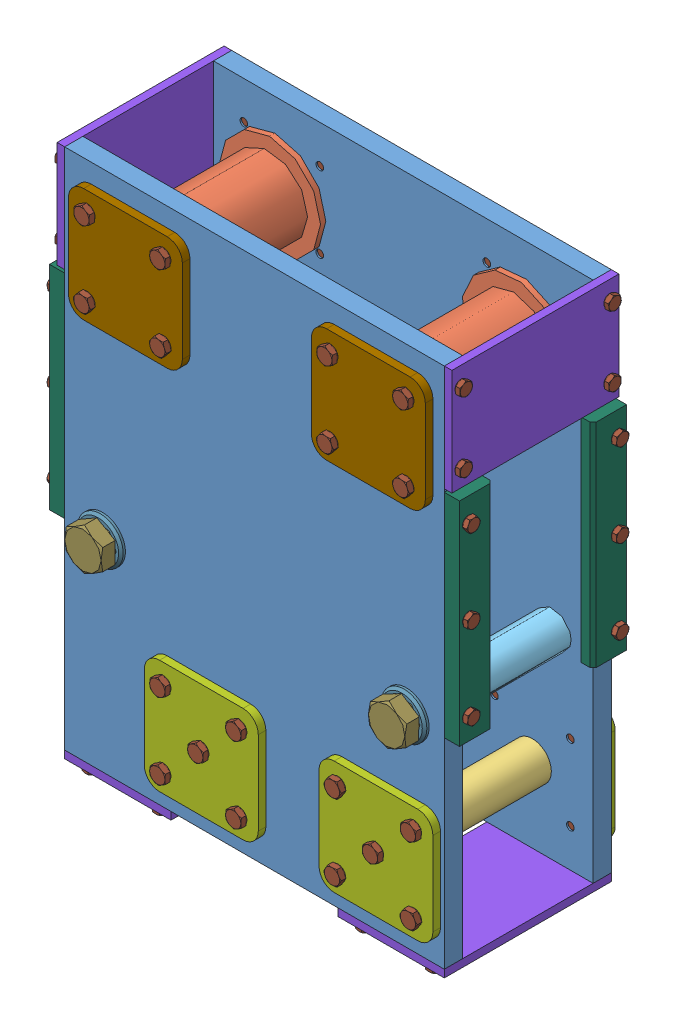
SolidWorks assembly 010200_trolley, configuration Default. Lengths in mm.
Overall size (277 352.5 150).
103 component instances, 15 part files, 227 mates.
Components (placement in the parent):
- 010201_trolley_main_plate-3: 010201_trolley_main_plate [Default] at (-125 -294 43) size (250 344 12)
- 010201_trolley_main_plate-1: 010201_trolley_main_plate [Default] at (-125 -294 -55) size (250 344 12)
- 010202_trolley_roller-1: 010202_trolley_roller [Default] at (-205 -50 0) size (67 67 105)
- 010202_trolley_roller-2: 010202_trolley_roller [Default] at (-45 -50 0) x (0.985719 -0.1684 0) z (0 0 1) size (67 67 105)
- 010203_trolley_cylinder_pin-1: 010203_trolley_cylinder_pin [Default] at (-40 -294 0) size (25 25 110)
- 010203_trolley_cylinder_pin-3: 010203_trolley_cylinder_pin [Default] at (-155 -294 0) size (25 25 110)
- 010204_trolley_winch-1: 010204_trolley_winch [Default] at (-155 -294 0) x (0 0 1) z (0 1 0) size (30 100 100)
- 010205_trolley_small_roll-2: 010205_trolley_small_roll [Default] at (-25 -211 0) size (24 24 83)
- 010205_trolley_small_roll-3: 010205_trolley_small_roll [Default] at (-225 -211 0) size (24 24 83)
- 010207_trolley_distance_sleeve-2: 010207_trolley_distance_sleeve [Default] at (-155 -294 29.5) size (32 32 27)
- 010207_trolley_distance_sleeve-1: 010207_trolley_distance_sleeve [Default] at (-155 -294 -29.5) size (32 32 27)
- 010209_trolley_pincover-6: 010209_trolley_pincover [Default] at (-40 -294 -55) x (0 1 0) z (0 0 -1) size (75 75 5)
- 010209_trolley_pincover-7: 010209_trolley_pincover [Default] at (-155 -294 55) x (-1 0 0) z (0 0 1) size (75 75 5)
- 010209_trolley_pincover-8: 010209_trolley_pincover [Default] at (-155 -294 -55) x (1 0 0) z (0 0 -1) size (75 75 5)
- 010210_trolley_front_plate-4: 010210_trolley_front_plate [Default] at (-252.5 -35 0) x (0 0 1) z (-1 0 0) size (110 70 5)
- 010210_trolley_front_plate-8: 010210_trolley_front_plate [Default] at (2.5 -35 0) x (0 0 -1) z (1 0 0) size (110 70 5)
- 010210_trolley_front_plate-9: 010210_trolley_front_plate [Default] at (-35 -346.5 0) x (0 0 1) z (0 -1 0) size (110 70 5)
- 010210_trolley_front_plate-10: 010210_trolley_front_plate [Default] at (-215 -346.5 0) x (0 0 1) z (0 -1 0) size (110 70 5)
- 010208_trolley_bearing_cover-1: 010208_trolley_bearing_cover [Default] at (-205 -50 55) size (75 75 5)
- 010208_trolley_bearing_cover-7: 010208_trolley_bearing_cover [Default] at (-45 -50 55) size (75 75 5)
- 010208_trolley_bearing_cover-8: 010208_trolley_bearing_cover [Default] at (-45 -50 -55) x (-1 0 0) z (0 0 -1) size (75 75 5)
- 010208_trolley_bearing_cover-9: 010208_trolley_bearing_cover [Default] at (-205 -50 -55) x (-1 0 0) z (0 0 -1) size (75 75 5)
- SKF_6005_2z-1: SKF_6005_2z [Default] at (-45 -50 -52.5) size (47 47 12)
- SKF_6005_2z-2: SKF_6005_2z [Default] at (-205 -50 -52.5) size (47 47 12)
- SKF_6005_2z-3: SKF_6005_2z [Default] at (-205 -50 40.5) size (47 47 12)
- SKF_6005_2z-4: SKF_6005_2z [Default] at (-45 -50 40.5) size (47 47 12)
- 010209_trolley_pincover-9: 010209_trolley_pincover [Default] at (-40 -294 55) x (0 -1 0) z (0 0 1) size (75 75 5)
- hex screw gradeab_iso-78: hex screw gradeab_iso [ISO 4017 - M6 x 16-N] at (-40 -294 64) x (0 0 -1) z (1 0 0) size (20 11.55 10)
- hex screw gradeab_iso-79: hex screw gradeab_iso [ISO 4017 - M6 x 16-N] at (-155 -294 -64) x (0 0 1) z (-0.804894 -0.593418 0) size (20 11.55 10)
- hex screw gradeab_iso-80: hex screw gradeab_iso [ISO 4017 - M6 x 16-N] at (-40 -294 -64) x (0 0 1) z (-0.923728 -0.383049 0) size (20 11.55 10)
- hex screw gradeab_iso-81: hex screw gradeab_iso [ISO 4017 - M6 x 16-N] at (-155 -294 64) x (0 0 -1) z (1 0 0) size (20 11.55 10)
- hex bolt gradeab_iso-3: hex bolt gradeab_iso [ISO 4014 - M16 x 140 x 44-N] at (-225 -211 68) x (0 0 -1) z (1 0 0) size (150 27.71 24)
- hex nut style 1 gradeab_iso-1: hex nut style 1 gradeab_iso [ISO - 4032 - M16 - W - N] at (-225 -211 -72.8) x (-1 0 0) z (0 0 -1) size (24 27.71 14.8)
- hex nut style 1 gradeab_iso-4: hex nut style 1 gradeab_iso [ISO - 4032 - M16 - W - N] at (-25 -211 -72.8) x (-0.534174 -0.845375 0) z (0 0 -1) size (24 27.71 14.8)
- plain washer chamfered grade a_iso-7: plain washer chamfered grade a_iso [Washer ISO 7090 - 16] at (-25 -211 55) x (0 0 -1) z (0.534174 0.845375 0) size (3 30 30)
- plain washer chamfered grade a_iso-8: plain washer chamfered grade a_iso [Washer ISO 7090 - 16] at (-25 -211 -55) x (0 0 1) z (-1 0 0) size (3 30 30)
- hex bolt gradeab_iso-4: hex bolt gradeab_iso [ISO 4014 - M16 x 140 x 44-N] at (-25 -211 68) x (0 0 -1) z (0.534174 0.845375 0) size (150 27.71 24)
- plain washer chamfered grade a_iso-4: plain washer chamfered grade a_iso [Washer ISO 7090 - 16] at (-225 -211 55) x (0 0 -1) z (1 0 0) size (3 30 30)
- plain washer chamfered grade a_iso-6: plain washer chamfered grade a_iso [Washer ISO 7090 - 16] at (-225 -211 -55) x (0 0 1) z (-1 0 0) size (3 30 30)
- hex screw gradeab_iso-98: hex screw gradeab_iso [ISO 4017 - M5 x 16-N] at (13.5 -142 49) x (-1 0 0) z (0 0 -1) size (19.5 9.24 8)
- hex screw gradeab_iso-99: hex screw gradeab_iso [ISO 4017 - M5 x 16-N] at (13.5 -87 49) x (-1 0 0) z (0 0.461604 0.887086) size (19.5 9.24 8)
- hex screw gradeab_iso-100: hex screw gradeab_iso [ISO 4017 - M5 x 16-N] at (13.5 -197 49) x (-1 0 0) z (0 -0.924225 -0.381849) size (19.5 9.24 8)
- hex screw gradeab_iso-101: hex screw gradeab_iso [ISO 4017 - M5 x 16-N] at (-263.5 -87 -49) x (1 0 0) z (0 0.461604 -0.887086) size (19.5 9.24 8)
- hex screw gradeab_iso-102: hex screw gradeab_iso [ISO 4017 - M5 x 16-N] at (-263.5 -197 -49) x (1 0 0) z (0 -0.924225 0.381849) size (19.5 9.24 8)
- hex screw gradeab_iso-103: hex screw gradeab_iso [ISO 4017 - M5 x 16-N] at (-263.5 -142 -49) size (19.5 9.24 8)
- hex screw gradeab_iso-104: hex screw gradeab_iso [ISO 4017 - M5 x 16-N] at (-263.5 -197 49) x (1 0 0) z (0 -0.461604 0.887086) size (19.5 9.24 8)
- hex screw gradeab_iso-105: hex screw gradeab_iso [ISO 4017 - M5 x 16-N] at (-263.5 -87 49) x (1 0 0) z (0 0.924225 -0.381849) size (19.5 9.24 8)
- hex screw gradeab_iso-106: hex screw gradeab_iso [ISO 4017 - M5 x 16-N] at (-263.5 -142 49) x (1 0 0) z (0 0 -1) size (19.5 9.24 8)
- hex screw gradeab_iso-107: hex screw gradeab_iso [ISO 4017 - M5 x 16-N] at (13.5 -197 -49) x (-1 0 0) z (0 -0.461604 -0.887086) size (19.5 9.24 8)
- hex screw gradeab_iso-108: hex screw gradeab_iso [ISO 4017 - M5 x 16-N] at (13.5 -87 -49) x (-1 0 0) z (0 0.924225 0.381849) size (19.5 9.24 8)
- hex screw gradeab_iso-109: hex screw gradeab_iso [ISO 4017 - M5 x 16-N] at (13.5 -142 -49) x (-1 0 0) z (0 0 1) size (19.5 9.24 8)
- hex screw gradeab_iso-65: hex screw gradeab_iso [ISO 4017 - M6 x 16-N] at (-15 -319 -64) x (0 0 1) z (0 1 0) size (20 11.55 10)
- hex screw gradeab_iso-66: hex screw gradeab_iso [ISO 4017 - M6 x 16-N] at (-15 -269 -64) x (0 0 1) z (-0.923728 -0.383049 0) size (20 11.55 10)
- hex screw gradeab_iso-67: hex screw gradeab_iso [ISO 4017 - M6 x 16-N] at (-65 -269 -64) x (0 0 1) z (0 1 0) size (20 11.55 10)
- hex screw gradeab_iso-68: hex screw gradeab_iso [ISO 4017 - M6 x 16-N] at (-65 -319 -64) x (0 0 1) z (0 1 0) size (20 11.55 10)
- hex screw gradeab_iso-82: hex screw gradeab_iso [ISO 4017 - M5 x 16-N] at (-258.5 -12 49) x (1 0 0) z (0 0.924225 0.381849) size (19.5 9.24 8)
- hex screw gradeab_iso-83: hex screw gradeab_iso [ISO 4017 - M5 x 16-N] at (-258.5 -12 -49) size (19.5 9.24 8)
- hex screw gradeab_iso-84: hex screw gradeab_iso [ISO 4017 - M5 x 16-N] at (-258.5 -58 49) size (19.5 9.24 8)
- hex screw gradeab_iso-85: hex screw gradeab_iso [ISO 4017 - M5 x 16-N] at (-258.5 -58 -49) size (19.5 9.24 8)
- hex screw gradeab_iso-90: hex screw gradeab_iso [ISO 4017 - M5 x 16-N] at (8.5 -12 -49) x (-1 0 0) z (0 0.93115 -0.364637) size (19.5 9.24 8)
- hex screw gradeab_iso-91: hex screw gradeab_iso [ISO 4017 - M5 x 16-N] at (8.5 -12 49) x (-1 0 0) z (0 0 -1) size (19.5 9.24 8)
- hex screw gradeab_iso-92: hex screw gradeab_iso [ISO 4017 - M5 x 16-N] at (8.5 -58 -49) x (-1 0 0) z (0 0 -1) size (19.5 9.24 8)
- hex screw gradeab_iso-93: hex screw gradeab_iso [ISO 4017 - M5 x 16-N] at (8.5 -58 49) x (-1 0 0) z (0 0 -1) size (19.5 9.24 8)
- hex screw gradeab_iso-86: hex screw gradeab_iso [ISO 4017 - M5 x 16-N] at (-58 -352.5 49) x (0 1 0) z (-0.924225 0 0.381849) size (19.5 9.24 8)
- hex screw gradeab_iso-87: hex screw gradeab_iso [ISO 4017 - M5 x 16-N] at (-58 -352.5 -49) x (0 1 0) z (0 0 1) size (19.5 9.24 8)
- hex screw gradeab_iso-88: hex screw gradeab_iso [ISO 4017 - M5 x 16-N] at (-12 -352.5 49) x (0 1 0) z (0 0 1) size (19.5 9.24 8)
- hex screw gradeab_iso-89: hex screw gradeab_iso [ISO 4017 - M5 x 16-N] at (-12 -352.5 -49) x (0 1 0) z (0 0 1) size (19.5 9.24 8)
- hex screw gradeab_iso-94: hex screw gradeab_iso [ISO 4017 - M5 x 16-N] at (-238 -352.5 49) x (0 1 0) z (-0.924225 0 0.381849) size (19.5 9.24 8)
- hex screw gradeab_iso-95: hex screw gradeab_iso [ISO 4017 - M5 x 16-N] at (-238 -352.5 -49) x (0 1 0) z (0 0 1) size (19.5 9.24 8)
- hex screw gradeab_iso-96: hex screw gradeab_iso [ISO 4017 - M5 x 16-N] at (-192 -352.5 49) x (0 1 0) z (0 0 1) size (19.5 9.24 8)
- hex screw gradeab_iso-97: hex screw gradeab_iso [ISO 4017 - M5 x 16-N] at (-192 -352.5 -49) x (0 1 0) z (0 0 1) size (19.5 9.24 8)
- hex screw gradeab_iso-25: hex screw gradeab_iso [ISO 4017 - M6 x 16-N] at (-180 -25 64) x (0 0 -1) z (1 0 0) size (20 11.55 10)
- hex screw gradeab_iso-26: hex screw gradeab_iso [ISO 4017 - M6 x 16-N] at (-230 -25 64) x (0 0 -1) z (1 0 0) size (20 11.55 10)
- hex screw gradeab_iso-27: hex screw gradeab_iso [ISO 4017 - M6 x 16-N] at (-230 -75 64) x (0 0 -1) z (0.923728 0.383049 0) size (20 11.55 10)
- hex screw gradeab_iso-28: hex screw gradeab_iso [ISO 4017 - M6 x 16-N] at (-180 -75 64) x (0 0 -1) z (0.923728 0.383049 0) size (20 11.55 10)
- hex screw gradeab_iso-29: hex screw gradeab_iso [ISO 4017 - M6 x 16-N] at (-20 -25 64) x (0 0 -1) z (1 0 0) size (20 11.55 10)
- hex screw gradeab_iso-30: hex screw gradeab_iso [ISO 4017 - M6 x 16-N] at (-70 -25 64) x (0 0 -1) z (1 0 0) size (20 11.55 10)
- hex screw gradeab_iso-31: hex screw gradeab_iso [ISO 4017 - M6 x 16-N] at (-70 -75 64) x (0 0 -1) z (0.923728 0.383049 0) size (20 11.55 10)
- hex screw gradeab_iso-32: hex screw gradeab_iso [ISO 4017 - M6 x 16-N] at (-20 -75 64) x (0 0 -1) z (0.923728 0.383049 0) size (20 11.55 10)
- hex screw gradeab_iso-33: hex screw gradeab_iso [ISO 4017 - M6 x 16-N] at (-70 -25 -64) x (0 0 1) z (-1 0 0) size (20 11.55 10)
- hex screw gradeab_iso-34: hex screw gradeab_iso [ISO 4017 - M6 x 16-N] at (-20 -25 -64) x (0 0 1) z (0.544188 0.838963 0) size (20 11.55 10)
- hex screw gradeab_iso-35: hex screw gradeab_iso [ISO 4017 - M6 x 16-N] at (-20 -75 -64) x (0 0 1) z (-0.923728 0.383049 0) size (20 11.55 10)
- hex screw gradeab_iso-36: hex screw gradeab_iso [ISO 4017 - M6 x 16-N] at (-70 -75 -64) x (0 0 1) z (-0.923728 0.383049 0) size (20 11.55 10)
- hex screw gradeab_iso-37: hex screw gradeab_iso [ISO 4017 - M6 x 16-N] at (-230 -25 -64) x (0 0 1) z (-1 0 0) size (20 11.55 10)
- hex screw gradeab_iso-38: hex screw gradeab_iso [ISO 4017 - M6 x 16-N] at (-180 -25 -64) x (0 0 1) z (-0.088811 0.996049 0) size (20 11.55 10)
- hex screw gradeab_iso-39: hex screw gradeab_iso [ISO 4017 - M6 x 16-N] at (-180 -75 -64) x (0 0 1) z (-0.923728 0.383049 0) size (20 11.55 10)
- hex screw gradeab_iso-40: hex screw gradeab_iso [ISO 4017 - M6 x 16-N] at (-230 -75 -64) x (0 0 1) z (-0.923728 0.383049 0) size (20 11.55 10)
- hex screw gradeab_iso-62: hex screw gradeab_iso [ISO 4017 - M6 x 16-N] at (-15 -269 64) x (0 0 -1) z (1 0 0) size (20 11.55 10)
- hex screw gradeab_iso-61: hex screw gradeab_iso [ISO 4017 - M6 x 16-N] at (-15 -319 64) x (0 0 -1) z (0 -1 0) size (20 11.55 10)
- hex screw gradeab_iso-63: hex screw gradeab_iso [ISO 4017 - M6 x 16-N] at (-65 -319 64) x (0 0 -1) z (0 -1 0) size (20 11.55 10)
- hex screw gradeab_iso-64: hex screw gradeab_iso [ISO 4017 - M6 x 16-N] at (-65 -269 64) x (0 0 -1) z (0 -1 0) size (20 11.55 10)
- hex screw gradeab_iso-69: hex screw gradeab_iso [ISO 4017 - M6 x 16-N] at (-130 -319 64) x (0 0 -1) z (-1 0 0) size (20 11.55 10)
- hex screw gradeab_iso-70: hex screw gradeab_iso [ISO 4017 - M6 x 16-N] at (-180 -319 64) x (0 0 -1) z (-1 0 0) size (20 11.55 10)
- hex screw gradeab_iso-71: hex screw gradeab_iso [ISO 4017 - M6 x 16-N] at (-180 -269 64) x (0 0 -1) z (-1 0 0) size (20 11.55 10)
- hex screw gradeab_iso-72: hex screw gradeab_iso [ISO 4017 - M6 x 16-N] at (-130 -269 64) x (0 0 -1) z (-1 0 0) size (20 11.55 10)
- hex screw gradeab_iso-73: hex screw gradeab_iso [ISO 4017 - M6 x 16-N] at (-180 -319 -64) x (0 0 1) z (1 0 0) size (20 11.55 10)
- hex screw gradeab_iso-74: hex screw gradeab_iso [ISO 4017 - M6 x 16-N] at (-130 -319 -64) x (0 0 1) z (1 0 0) size (20 11.55 10)
- hex screw gradeab_iso-75: hex screw gradeab_iso [ISO 4017 - M6 x 16-N] at (-130 -269 -64) x (0 0 1) z (1 0 0) size (20 11.55 10)
- hex screw gradeab_iso-76: hex screw gradeab_iso [ISO 4017 - M6 x 16-N] at (-180 -269 -64) x (0 0 1) z (-0.677902 -0.735152 0) size (20 11.55 10)
- 010206_trolley_guide-1: 010206_trolley_guide [Default] at (0 -142 44) x (0 0 -1) z (1 0 0) size (22 140 10)
- 010206_trolley_guide-5: 010206_trolley_guide [Default] at (-250 -142 -44) x (0 0 1) z (-1 0 0) size (22 140 10)
- 010206_trolley_guide-6: 010206_trolley_guide [Default] at (-250 -142 44) x (0 0 -1) z (-1 0 0) size (22 140 10)
- 010206_trolley_guide-7: 010206_trolley_guide [Default] at (0 -142 -44) x (0 0 1) z (1 0 0) size (22 140 10)
Mates (geometry in assembly coordinates):
- Concentric2: concentric aligned: cylinder of 010201_trolley_main_plate-1 through (-45 -50 -43) axis (0 0 -1) radius 23.5; cylinder of SKF_6005_2z-1 through (-45 -50 -40.5) axis (0 0 -1) radius 23.5
- Concentric3: concentric aligned: cylinder of 010201_trolley_main_plate-1 through (-205 -50 -43) axis (0 0 -1) radius 23.5; cylinder of SKF_6005_2z-2 through (-205 -50 -40.5) axis (0 0 -1) radius 12.5
- Concentric4: concentric aligned: cylinder of 010202_trolley_roller-1 through (-205 -50 0) axis (0 0 1) radius 16; circle of SKF_6005_2z-2
- Concentric14: concentric aligned: cylinder of SKF_6005_2z-4 through (-45 -50 52.5) axis (0 0 -1) radius 23.5; cylinder of 010201_trolley_main_plate-3 through (-45 -50 55) axis (0 0 -1) radius 23.5
- Concentric15: concentric aligned: cylinder of SKF_6005_2z-3 through (-205 -50 52.5) axis (0 0 -1) radius 12.5; cylinder of 010201_trolley_main_plate-3 through (-205 -50 55) axis (0 0 -1) radius 23.5
- Concentric16: concentric anti-aligned: cylinder of 010202_trolley_roller-2 through (-45 -50 0) axis (0 0 1) radius 16; cylinder of SKF_6005_2z-4 through (-45 -50 52.5) axis (0 0 -1) radius 12.5
- Concentric17: concentric anti-aligned: cylinder of 010202_trolley_roller-1 through (-205 -50 0) axis (0 0 1) radius 16; cylinder of SKF_6005_2z-3 through (-205 -50 52.5) axis (0 0 -1) radius 12.5
- Coincident13: coincident aligned: plane of 010201_trolley_main_plate-3 through (-125 -294 55) normal (0 0 1); plane of 010203_trolley_cylinder_pin-1 through (-40 -294 55) normal (0 0 1)
- Coincident14: coincident aligned: plane of 010202_trolley_roller-1 through (-205 -50 0) normal (0 0 1)
- Coincident15: coincident aligned: plane of 010201_trolley_main_plate-1 through (-250 0 -43) normal (0 1 0)
- Coincident16: coincident aligned: plane of 010201_trolley_main_plate-1 through (0 0 -43) normal (1 0 0)
- Concentric18: concentric aligned: cylinder of 010201_trolley_main_plate-1 through (-40 -294 -43) axis (0 0 -1) radius 12.5; cylinder of 010203_trolley_cylinder_pin-1 through (-40 -294 55) axis (0 0 -1) radius 12.5
- Parallel1: parallel aligned: plane of 010201_trolley_main_plate-1 through (-125 -294 -55) normal (0 0 -1); plane of 010203_trolley_cylinder_pin-1 through (-40 -294 -55) normal (0 0 -1)
- Coincident30: coincident aligned: plane of 010205_trolley_small_roll-2 through (-25 -211 0) normal (0 0 1)
- Coincident31: coincident aligned: plane of 010205_trolley_small_roll-3 through (-225 -211 0) normal (0 0 1)
- Coincident33: coincident aligned: plane of 010201_trolley_main_plate-3 through (-125 -294 55) normal (0 0 1); plane of 010206_trolley_guide-1 through (10 -212 55) normal (0 0 1)
- Coincident34: coincident anti-aligned: plane of 010201_trolley_main_plate-3 through (0 0 55) normal (1 0 0); plane of 010206_trolley_guide-1 through (0 -142 44) normal (-1 0 0)
- Concentric22: concentric anti-aligned: cylinder of 010201_trolley_main_plate-3 through (-225 -211 55) axis (0 0 -1) radius 8.5; cylinder of hex bolt gradeab_iso-3 through (-225 -211 68) axis (0 0 1) radius 8
- Coincident48: coincident anti-aligned: plane of hex bolt gradeab_iso-3 through (-225 -197.1436 58) normal (0 0 -1); plane of plain washer chamfered grade a_iso-4 through (-225 -197.5 58) normal (0 0 1)
- Concentric23: concentric aligned: cylinder of hex bolt gradeab_iso-3 through (-225 -211 68) axis (0 0 1) radius 8; cylinder of plain washer chamfered grade a_iso-4 through (-225 -211 89.925) axis (0 0 1) radius 8.5
- Concentric24: concentric anti-aligned: cylinder of hex bolt gradeab_iso-3 through (-225 -211 68) axis (0 0 1) radius 8; cylinder of hex nut style 1 gradeab_iso-1 through (-225 -211 -58) axis (0 0 -1) radius 7
- Coincident49: coincident anti-aligned: plane of hex nut style 1 gradeab_iso-1 through (-225 -197.1436 -58) normal (0 0 1); plane of plain washer chamfered grade a_iso-6 through (-225 -197.5 -58) normal (0 0 -1)
- Coincident50: coincident anti-aligned: plane of 010201_trolley_main_plate-3 through (-125 -294 55) normal (0 0 1); plane of plain washer chamfered grade a_iso-4 through (-225 -202.5 55) normal (0 0 -1)
- Coincident51: coincident anti-aligned: plane of hex nut style 1 gradeab_iso-4 through (-36.7139 -203.5983 -58) normal (0 0 1); plane of plain washer chamfered grade a_iso-8 through (-25 -197.5 -58) normal (0 0 -1)
- Concentric25: concentric aligned: cylinder of plain washer chamfered grade a_iso-7 through (-25 -211 89.925) axis (0 0 1) radius 8.5; cylinder of hex bolt gradeab_iso-4 through (-25 -211 68) axis (0 0 1) radius 8
- Coincident52: coincident anti-aligned: plane of plain washer chamfered grade a_iso-7 through (-36.4126 -203.7887 58) normal (0 0 1); plane of hex bolt gradeab_iso-4 through (-36.7139 -203.5983 58) normal (0 0 -1)
- Concentric26: concentric anti-aligned: cylinder of hex nut style 1 gradeab_iso-4 through (-25 -211 -58) axis (0 0 -1) radius 7; cylinder of hex bolt gradeab_iso-4 through (-25 -211 68) axis (0 0 1) radius 8
- Concentric27: concentric anti-aligned: cylinder of plain washer chamfered grade a_iso-8 through (-25 -211 -89.925) axis (0 0 -1) radius 8.5; cylinder of hex bolt gradeab_iso-4 through (-25 -211 68) axis (0 0 1) radius 8
- Concentric28: concentric aligned: cylinder of hex nut style 1 gradeab_iso-4 through (-25 -211 -58) axis (0 0 -1) radius 7; cylinder of plain washer chamfered grade a_iso-8 through (-25 -211 -89.925) axis (0 0 -1) radius 8.5
- Concentric29: concentric anti-aligned: cylinder of 010201_trolley_main_plate-3 through (-25 -211 55) axis (0 0 -1) radius 8.5; cylinder of hex bolt gradeab_iso-4 through (-25 -211 68) axis (0 0 1) radius 8
- Coincident53: coincident anti-aligned: plane of 010201_trolley_main_plate-3 through (-125 -294 55) normal (0 0 1); plane of plain washer chamfered grade a_iso-7 through (-32.1857 -206.4595 55) normal (0 0 -1)
- Coincident54: coincident anti-aligned: plane of 010201_trolley_main_plate-1 through (-125 -294 -55) normal (0 0 -1); plane of plain washer chamfered grade a_iso-8 through (-25 -202.5 -55) normal (0 0 1)
- Coincident55: coincident anti-aligned: plane of 010201_trolley_main_plate-1 through (-125 -294 -55) normal (0 0 -1); plane of plain washer chamfered grade a_iso-6 through (-225 -202.5 -55) normal (0 0 1)
- Concentric31: concentric anti-aligned: cylinder of hex bolt gradeab_iso-3 through (-225 -211 68) axis (0 0 1) radius 8; cylinder of plain washer chamfered grade a_iso-6 through (-225 -211 -89.925) axis (0 0 -1) radius 8.5
- Concentric37: concentric anti-aligned: cylinder of 010205_trolley_small_roll-2 through (-25 -211 41.5) axis (0 0 -1) radius 8.5; cylinder of hex bolt gradeab_iso-4 through (-25 -211 68) axis (0 0 1) radius 8
- Concentric38: concentric anti-aligned: cylinder of 010205_trolley_small_roll-3 through (-225 -211 41.5) axis (0 0 -1) radius 12; cylinder of hex bolt gradeab_iso-3 through (-225 -211 68) axis (0 0 1) radius 8
- Coincident64: coincident aligned: plane of 010201_trolley_main_plate-1 through (-125 -294 -55) normal (0 0 -1); plane of 010210_trolley_front_plate-4 through (-255 0 -55) normal (0 0 -1)
- Coincident65: coincident anti-aligned: plane of 010201_trolley_main_plate-1 through (-250 -344 -43) normal (-1 0 0); plane of 010210_trolley_front_plate-4 through (-250 -35 0) normal (1 0 0)
- Coincident66: coincident aligned: plane of 010201_trolley_main_plate-1 through (-250 0 -43) normal (0 1 0); plane of 010210_trolley_front_plate-4 through (-255 0 -55) normal (0 1 0)
- Concentric39: concentric aligned: cylinder of 010201_trolley_main_plate-3 through (-230 -25 55) axis (0 0 1) radius 2.5; cylinder of 010208_trolley_bearing_cover-1 through (-230 -25 60) axis (0 0 1) radius 3.5
- Concentric40: concentric aligned: cylinder of 010201_trolley_main_plate-3 through (-180 -25 55) axis (0 0 1) radius 2.5; cylinder of 010208_trolley_bearing_cover-1 through (-180 -25 60) axis (0 0 1) radius 3.5
- Coincident67: coincident anti-aligned: plane of 010201_trolley_main_plate-3 through (-125 -294 55) normal (0 0 1); plane of 010208_trolley_bearing_cover-1 through (-205 -50 55) normal (0 0 -1)
- Coincident102: coincident aligned: plane of trolley_winch-1 through (-155 -294 0) normal (0 0 1)
- Parallel2: parallel anti-aligned: plane of 010201_trolley_main_plate-1 through (-250 -344 -43) normal (-1 0 0); plane of trolley_winch-1 through (-115 -294 0) normal (1 0 0)
- Concentric91: concentric aligned: cylinder of 010208_trolley_bearing_cover-1 through (-230 -25 60) axis (0 0 1) radius 3.5; cylinder of hex screw gradeab_iso-26 through (-230 -25 64) axis (0 0 1) radius 3
- Concentric92: concentric aligned: cylinder of 010208_trolley_bearing_cover-1 through (-180 -25 60) axis (0 0 1) radius 3.5; cylinder of hex screw gradeab_iso-25 through (-180 -25 64) axis (0 0 1) radius 3
- Concentric93: concentric aligned: cylinder of 010208_trolley_bearing_cover-1 through (-230 -75 60) axis (0 0 1) radius 3.5; cylinder of hex screw gradeab_iso-27 through (-230 -75 64) axis (0 0 1) radius 3
- Concentric94: concentric aligned: cylinder of 010208_trolley_bearing_cover-1 through (-180 -75 60) axis (0 0 1) radius 3.5; cylinder of hex screw gradeab_iso-28 through (-180 -75 64) axis (0 0 1) radius 3
- Coincident109: coincident anti-aligned: plane of 010208_trolley_bearing_cover-1 through (-205 -50 60) normal (0 0 1); plane of hex screw gradeab_iso-26 through (-230 -19.2265 60) normal (0 0 -1)
- Coincident110: coincident anti-aligned: plane of 010208_trolley_bearing_cover-1 through (-205 -50 60) normal (0 0 1); plane of hex screw gradeab_iso-28 through (-182.2115 -69.6669 60) normal (0 0 -1)
- Coincident111: coincident anti-aligned: plane of 010208_trolley_bearing_cover-1 through (-205 -50 60) normal (0 0 1); plane of hex screw gradeab_iso-27 through (-232.2115 -69.6669 60) normal (0 0 -1)
- Coincident112: coincident anti-aligned: plane of 010208_trolley_bearing_cover-1 through (-205 -50 60) normal (0 0 1); plane of hex screw gradeab_iso-25 through (-180 -19.2265 60) normal (0 0 -1)
- Concentric95: concentric aligned: cylinder of hex screw gradeab_iso-30 through (-70 -25 64) axis (0 0 1) radius 3; cylinder of 010208_trolley_bearing_cover-7 through (-70 -25 60) axis (0 0 1) radius 3.5
- Concentric96: concentric aligned: cylinder of hex screw gradeab_iso-31 through (-70 -75 64) axis (0 0 1) radius 3; cylinder of 010208_trolley_bearing_cover-7 through (-70 -75 60) axis (0 0 1) radius 3.5
- Concentric97: concentric aligned: cylinder of hex screw gradeab_iso-29 through (-20 -25 64) axis (0 0 1) radius 3; cylinder of 010208_trolley_bearing_cover-7 through (-20 -25 60) axis (0 0 1) radius 3.5
- Concentric98: concentric aligned: cylinder of hex screw gradeab_iso-32 through (-20 -75 64) axis (0 0 1) radius 3; cylinder of 010208_trolley_bearing_cover-7 through (-20 -75 60) axis (0 0 1) radius 3.5
- Coincident113: coincident anti-aligned: plane of hex screw gradeab_iso-30 through (-70 -19.2265 60) normal (0 0 -1); plane of 010208_trolley_bearing_cover-7 through (-45 -50 60) normal (0 0 1)
- Coincident114: coincident anti-aligned: plane of hex screw gradeab_iso-32 through (-22.2115 -69.6669 60) normal (0 0 -1); plane of 010208_trolley_bearing_cover-7 through (-45 -50 60) normal (0 0 1)
- Coincident115: coincident anti-aligned: plane of hex screw gradeab_iso-31 through (-72.2115 -69.6669 60) normal (0 0 -1); plane of 010208_trolley_bearing_cover-7 through (-45 -50 60) normal (0 0 1)
- Coincident116: coincident anti-aligned: plane of hex screw gradeab_iso-29 through (-20 -19.2265 60) normal (0 0 -1); plane of 010208_trolley_bearing_cover-7 through (-45 -50 60) normal (0 0 1)
- Concentric99: concentric aligned: cylinder of hex screw gradeab_iso-34 through (-20 -25 -64) axis (0 0 -1) radius 3; cylinder of 010208_trolley_bearing_cover-8 through (-20 -25 -60) axis (0 0 -1) radius 3.5
- Concentric100: concentric aligned: cylinder of hex screw gradeab_iso-35 through (-20 -75 -64) axis (0 0 -1) radius 3; cylinder of 010208_trolley_bearing_cover-8 through (-20 -75 -60) axis (0 0 -1) radius 3.5
- Concentric101: concentric aligned: cylinder of hex screw gradeab_iso-33 through (-70 -25 -64) axis (0 0 -1) radius 3; cylinder of 010208_trolley_bearing_cover-8 through (-70 -25 -60) axis (0 0 -1) radius 3.5
- Concentric102: concentric aligned: cylinder of hex screw gradeab_iso-36 through (-70 -75 -64) axis (0 0 -1) radius 3; cylinder of 010208_trolley_bearing_cover-8 through (-70 -75 -60) axis (0 0 -1) radius 3.5
- Coincident117: coincident anti-aligned: plane of hex screw gradeab_iso-34 through (-15.1562 -28.1419 -60) normal (0 0 1); plane of 010208_trolley_bearing_cover-8 through (-45 -50 -60) normal (0 0 -1)
- Coincident118: coincident anti-aligned: plane of hex screw gradeab_iso-36 through (-67.7885 -69.6669 -60) normal (0 0 1); plane of 010208_trolley_bearing_cover-8 through (-45 -50 -60) normal (0 0 -1)
- Coincident119: coincident anti-aligned: plane of hex screw gradeab_iso-35 through (-17.7885 -69.6669 -60) normal (0 0 1); plane of 010208_trolley_bearing_cover-8 through (-45 -50 -60) normal (0 0 -1)
- Coincident120: coincident anti-aligned: plane of hex screw gradeab_iso-33 through (-70 -19.2265 -60) normal (0 0 1); plane of 010208_trolley_bearing_cover-8 through (-45 -50 -60) normal (0 0 -1)
- Concentric103: concentric aligned: cylinder of hex screw gradeab_iso-38 through (-180 -25 -64) axis (0 0 -1) radius 3; cylinder of 010208_trolley_bearing_cover-9 through (-180 -25 -60) axis (0 0 -1) radius 3.5
- Concentric104: concentric aligned: cylinder of hex screw gradeab_iso-39 through (-180 -75 -64) axis (0 0 -1) radius 3; cylinder of 010208_trolley_bearing_cover-9 through (-180 -75 -60) axis (0 0 -1) radius 3.5
- Concentric105: concentric aligned: cylinder of hex screw gradeab_iso-37 through (-230 -25 -64) axis (0 0 -1) radius 3; cylinder of 010208_trolley_bearing_cover-9 through (-230 -25 -60) axis (0 0 -1) radius 3.5
- Concentric106: concentric aligned: cylinder of hex screw gradeab_iso-40 through (-230 -75 -64) axis (0 0 -1) radius 3; cylinder of 010208_trolley_bearing_cover-9 through (-230 -75 -60) axis (0 0 -1) radius 3.5
- Coincident121: coincident anti-aligned: plane of hex screw gradeab_iso-38 through (-174.2493 -24.4873 -60) normal (0 0 1); plane of 010208_trolley_bearing_cover-9 through (-205 -50 -60) normal (0 0 -1)
- Coincident122: coincident anti-aligned: plane of hex screw gradeab_iso-40 through (-227.7885 -69.6669 -60) normal (0 0 1); plane of 010208_trolley_bearing_cover-9 through (-205 -50 -60) normal (0 0 -1)
- Coincident123: coincident anti-aligned: plane of hex screw gradeab_iso-39 through (-177.7885 -69.6669 -60) normal (0 0 1); plane of 010208_trolley_bearing_cover-9 through (-205 -50 -60) normal (0 0 -1)
- Coincident124: coincident anti-aligned: plane of hex screw gradeab_iso-37 through (-230 -19.2265 -60) normal (0 0 1); plane of 010208_trolley_bearing_cover-9 through (-205 -50 -60) normal (0 0 -1)
- Coincident145: coincident anti-aligned: plane of 010201_trolley_main_plate-3 through (-125 -294 55) normal (0 0 1); plane of 010208_trolley_bearing_cover-7 through (-45 -50 55) normal (0 0 -1)
- Concentric127: concentric aligned: cylinder of 010201_trolley_main_plate-3 through (-70 -25 55) axis (0 0 1) radius 2.5; cylinder of hex screw gradeab_iso-30 through (-70 -25 64) axis (0 0 1) radius 3
- Concentric128: concentric aligned: cylinder of 010201_trolley_main_plate-3 through (-20 -75 55) axis (0 0 1) radius 2.5; cylinder of hex screw gradeab_iso-32 through (-20 -75 64) axis (0 0 1) radius 3
- Coincident146: coincident anti-aligned: plane of 010201_trolley_main_plate-1 through (-125 -294 -55) normal (0 0 -1); plane of 010208_trolley_bearing_cover-8 through (-45 -50 -55) normal (0 0 1)
- Coincident147: coincident anti-aligned: plane of 010201_trolley_main_plate-1 through (-125 -294 -55) normal (0 0 -1); plane of 010208_trolley_bearing_cover-9 through (-205 -50 -55) normal (0 0 1)
- Concentric129: concentric anti-aligned: cylinder of 010201_trolley_main_plate-1 through (-20 -25 -43) axis (0 0 1) radius 2.5; cylinder of hex screw gradeab_iso-34 through (-20 -25 -64) axis (0 0 -1) radius 3
- Concentric130: concentric anti-aligned: circle of Trolley_main_plate-1; cylinder of hex screw gradeab_iso-38 through (-180 -25 -64) axis (0 0 -1) radius 3
- Concentric133: concentric anti-aligned: cylinder of 010201_trolley_main_plate-1 through (-230 -75 -43) axis (0 0 1) radius 2.5; cylinder of hex screw gradeab_iso-40 through (-230 -75 -64) axis (0 0 -1) radius 3
- Concentric134: concentric anti-aligned: cylinder of 010201_trolley_main_plate-1 through (-70 -75 -43) axis (0 0 1) radius 2.5; cylinder of hex screw gradeab_iso-36 through (-70 -75 -64) axis (0 0 -1) radius 3
- Concentric135: concentric aligned: cylinder of hex screw gradeab_iso-61 through (-15 -319 64) axis (0 0 1) radius 3; cylinder of 010209_trolley_pincover-9 through (-15 -319 60) axis (0 0 1) radius 3.5
- Concentric136: concentric aligned: circle of trolley_pincover-5; cylinder of hex screw gradeab_iso-62 through (-15 -269 64) axis (0 0 1) radius 3
- Concentric137: concentric aligned: cylinder of 010209_trolley_pincover-9 through (-65 -319 60) axis (0 0 1) radius 3.5; cylinder of hex screw gradeab_iso-63 through (-65 -319 64) axis (0 0 1) radius 3
- Concentric138: concentric aligned: cylinder of 010209_trolley_pincover-9 through (-65 -269 60) axis (0 0 1) radius 3.5; cylinder of hex screw gradeab_iso-64 through (-65 -269 64) axis (0 0 1) radius 3
- Coincident148: coincident anti-aligned: plane of hex screw gradeab_iso-61 through (-9.2265 -319 60) normal (0 0 -1); plane of 010209_trolley_pincover-9 through (-40 -294 60) normal (0 0 1)
- Coincident149: coincident anti-aligned: plane of 010209_trolley_pincover-9 through (-40 -294 60) normal (0 0 1); plane of hex screw gradeab_iso-62 through (-15 -263.2265 60) normal (0 0 -1)
- Coincident150: coincident anti-aligned: plane of 010209_trolley_pincover-9 through (-40 -294 60) normal (0 0 1); plane of hex screw gradeab_iso-63 through (-59.2265 -319 60) normal (0 0 -1)
- Coincident151: coincident anti-aligned: plane of 010209_trolley_pincover-9 through (-40 -294 60) normal (0 0 1); plane of hex screw gradeab_iso-64 through (-59.2265 -269 60) normal (0 0 -1)
- Coincident152: coincident anti-aligned: plane of hex screw gradeab_iso-66 through (-17.2115 -263.6669 -60) normal (0 0 1); plane of 010209_trolley_pincover-6 through (-40 -294 -60) normal (0 0 -1)
- Concentric139: concentric aligned: cylinder of hex screw gradeab_iso-68 through (-65 -319 -64) axis (0 0 -1) radius 3; cylinder of 010209_trolley_pincover-6 through (-65 -319 -60) axis (0 0 -1) radius 3.5
- Coincident153: coincident anti-aligned: plane of hex screw gradeab_iso-65 through (-9.2265 -319 -60) normal (0 0 1); plane of 010209_trolley_pincover-6 through (-40 -294 -60) normal (0 0 -1)
- Coincident154: coincident anti-aligned: plane of hex screw gradeab_iso-68 through (-59.2265 -319 -60) normal (0 0 1); plane of 010209_trolley_pincover-6 through (-40 -294 -60) normal (0 0 -1)
- Concentric140: concentric aligned: cylinder of hex screw gradeab_iso-66 through (-15 -269 -64) axis (0 0 -1) radius 3; cylinder of 010209_trolley_pincover-6 through (-15 -269 -60) axis (0 0 -1) radius 3.5
- Concentric141: concentric aligned: cylinder of hex screw gradeab_iso-67 through (-65 -269 -64) axis (0 0 -1) radius 3; cylinder of 010209_trolley_pincover-6 through (-65 -269 -60) axis (0 0 -1) radius 3.5
- Concentric142: concentric aligned: cylinder of hex screw gradeab_iso-65 through (-15 -319 -64) axis (0 0 -1) radius 3; circle of trolley_pincover-6
- Coincident155: coincident anti-aligned: plane of hex screw gradeab_iso-67 through (-59.2265 -269 -60) normal (0 0 1); plane of 010209_trolley_pincover-6 through (-40 -294 -60) normal (0 0 -1)
- Coincident156: coincident anti-aligned: plane of hex screw gradeab_iso-70 through (-180 -324.7735 60) normal (0 0 -1); plane of 010209_trolley_pincover-7 through (-155 -294 60) normal (0 0 1)
- Concentric143: concentric aligned: cylinder of hex screw gradeab_iso-72 through (-130 -269 64) axis (0 0 1) radius 3; cylinder of 010209_trolley_pincover-7 through (-130 -269 60) axis (0 0 1) radius 3.5
- Coincident157: coincident anti-aligned: plane of hex screw gradeab_iso-69 through (-130 -324.7735 60) normal (0 0 -1); plane of 010209_trolley_pincover-7 through (-155 -294 60) normal (0 0 1)
- Coincident158: coincident anti-aligned: plane of hex screw gradeab_iso-72 through (-130 -274.7735 60) normal (0 0 -1); plane of 010209_trolley_pincover-7 through (-155 -294 60) normal (0 0 1)
- Concentric144: concentric aligned: cylinder of hex screw gradeab_iso-70 through (-180 -319 64) axis (0 0 1) radius 3; cylinder of 010209_trolley_pincover-7 through (-180 -319 60) axis (0 0 1) radius 3.5
- Concentric145: concentric aligned: cylinder of hex screw gradeab_iso-71 through (-180 -269 64) axis (0 0 1) radius 3; cylinder of 010209_trolley_pincover-7 through (-180 -269 60) axis (0 0 1) radius 3.5
- Concentric146: concentric aligned: cylinder of hex screw gradeab_iso-69 through (-130 -319 64) axis (0 0 1) radius 3; circle of trolley_pincover-7
- Coincident159: coincident anti-aligned: plane of hex screw gradeab_iso-71 through (-180 -274.7735 60) normal (0 0 -1); plane of 010209_trolley_pincover-7 through (-155 -294 60) normal (0 0 1)
- Coincident160: coincident anti-aligned: plane of hex screw gradeab_iso-74 through (-130 -324.7735 -60) normal (0 0 1); plane of 010209_trolley_pincover-8 through (-155 -294 -60) normal (0 0 -1)
- Concentric147: concentric aligned: cylinder of hex screw gradeab_iso-76 through (-180 -269 -64) axis (0 0 -1) radius 3; cylinder of 010209_trolley_pincover-8 through (-180 -269 -60) axis (0 0 -1) radius 3.5
- Coincident161: coincident anti-aligned: plane of hex screw gradeab_iso-73 through (-180 -324.7735 -60) normal (0 0 1); plane of 010209_trolley_pincover-8 through (-155 -294 -60) normal (0 0 -1)
- Coincident162: coincident anti-aligned: plane of hex screw gradeab_iso-76 through (-184.2444 -265.0861 -60) normal (0 0 1); plane of 010209_trolley_pincover-8 through (-155 -294 -60) normal (0 0 -1)
- Concentric148: concentric aligned: cylinder of hex screw gradeab_iso-74 through (-130 -319 -64) axis (0 0 -1) radius 3; cylinder of 010209_trolley_pincover-8 through (-130 -319 -60) axis (0 0 -1) radius 3.5
- Concentric149: concentric aligned: cylinder of hex screw gradeab_iso-75 through (-130 -269 -64) axis (0 0 -1) radius 3; cylinder of 010209_trolley_pincover-8 through (-130 -269 -60) axis (0 0 -1) radius 3.5
- Concentric150: concentric aligned: cylinder of hex screw gradeab_iso-73 through (-180 -319 -64) axis (0 0 -1) radius 3; circle of trolley_pincover-8
- Coincident163: coincident anti-aligned: plane of hex screw gradeab_iso-75 through (-130 -274.7735 -60) normal (0 0 1); plane of 010209_trolley_pincover-8 through (-155 -294 -60) normal (0 0 -1)
- Coincident164: coincident anti-aligned: plane of 010201_trolley_main_plate-3 through (-125 -294 55) normal (0 0 1); plane of 010209_trolley_pincover-9 through (-40 -294 55) normal (0 0 -1)
- Coincident165: coincident anti-aligned: plane of 010201_trolley_main_plate-3 through (-125 -294 55) normal (0 0 1); plane of 010209_trolley_pincover-7 through (-155 -294 55) normal (0 0 -1)
- Coincident166: coincident anti-aligned: plane of 010201_trolley_main_plate-1 through (-125 -294 -55) normal (0 0 -1); plane of 010209_trolley_pincover-8 through (-155 -294 -55) normal (0 0 1)
- Coincident167: coincident anti-aligned: plane of 010201_trolley_main_plate-1 through (-125 -294 -55) normal (0 0 -1); plane of 010209_trolley_pincover-6 through (-40 -294 -55) normal (0 0 1)
- Concentric151: concentric anti-aligned: cylinder of 010201_trolley_main_plate-1 through (-15 -269 -43) axis (0 0 1) radius 2.5; cylinder of hex screw gradeab_iso-66 through (-15 -269 -64) axis (0 0 -1) radius 3
- Concentric152: concentric anti-aligned: circle of Trolley_main_plate-1; cylinder of hex screw gradeab_iso-76 through (-180 -269 -64) axis (0 0 -1) radius 3
- Concentric153: concentric aligned: circle of Trolley_main_plate-3; cylinder of hex screw gradeab_iso-62 through (-15 -269 64) axis (0 0 1) radius 3
- Concentric154: concentric aligned: circle of Trolley_main_plate-3; cylinder of hex screw gradeab_iso-69 through (-130 -319 64) axis (0 0 1) radius 3
- Concentric155: concentric aligned: cylinder of 010201_trolley_main_plate-3 through (-180 -269 55) axis (0 0 1) radius 2.5; cylinder of hex screw gradeab_iso-71 through (-180 -269 64) axis (0 0 1) radius 3
- Concentric157: concentric aligned: cylinder of 010201_trolley_main_plate-3 through (-65 -319 55) axis (0 0 1) radius 2.5; cylinder of hex screw gradeab_iso-63 through (-65 -319 64) axis (0 0 1) radius 3
- Concentric158: concentric anti-aligned: cylinder of 010201_trolley_main_plate-1 through (-65 -319 -43) axis (0 0 1) radius 2.5; cylinder of hex screw gradeab_iso-68 through (-65 -319 -64) axis (0 0 -1) radius 3
- Concentric159: concentric anti-aligned: cylinder of 010201_trolley_main_plate-1 through (-130 -319 -43) axis (0 0 1) radius 2.5; cylinder of hex screw gradeab_iso-74 through (-130 -319 -64) axis (0 0 -1) radius 3
- Concentric160: concentric aligned: cylinder of 010201_trolley_main_plate-3 through (-155 -294 55) axis (0 0 -1) radius 12.5; cylinder of 010203_trolley_cylinder_pin-3 through (-155 -294 55) axis (0 0 -1) radius 12.5
- Coincident168: coincident aligned: plane of 010201_trolley_main_plate-1 through (-125 -294 -55) normal (0 0 -1); plane of 010203_trolley_cylinder_pin-3 through (-155 -294 -55) normal (0 0 -1)
- Concentric161: concentric aligned: cylinder of trolley_winch-1 through (-155 -294 -75.8883) axis (0 0 -1) radius 12.5; cylinder of 010203_trolley_cylinder_pin-3 through (-155 -294 55) axis (0 0 -1) radius 12.5
- Concentric163: concentric aligned: cylinder of 010209_trolley_pincover-7 through (-155 -294 60) axis (0 0 1) radius 3.5; cylinder of hex screw gradeab_iso-81 through (-155 -294 64) axis (0 0 1) radius 3
- Concentric164: concentric aligned: cylinder of 010209_trolley_pincover-9 through (-40 -294 60) axis (0 0 1) radius 3.5; cylinder of hex screw gradeab_iso-78 through (-40 -294 64) axis (0 0 1) radius 3
- Concentric166: concentric aligned: cylinder of 010209_trolley_pincover-8 through (-155 -294 -60) axis (0 0 -1) radius 3.5; cylinder of hex screw gradeab_iso-79 through (-155 -294 -64) axis (0 0 -1) radius 3
- Concentric167: concentric aligned: circle of trolley_pincover-6; cylinder of hex screw gradeab_iso-80 through (-40 -294 -64) axis (0 0 -1) radius 3
- Coincident169: coincident anti-aligned: plane of 010209_trolley_pincover-6 through (-40 -294 -60) normal (0 0 -1); plane of hex screw gradeab_iso-80 through (-42.2115 -288.6669 -60) normal (0 0 1)
- Coincident171: coincident anti-aligned: plane of 010209_trolley_pincover-8 through (-155 -294 -60) normal (0 0 -1); plane of hex screw gradeab_iso-79 through (-158.4261 -289.3529 -60) normal (0 0 1)
- Coincident172: coincident anti-aligned: plane of 010209_trolley_pincover-7 through (-155 -294 60) normal (0 0 1); plane of hex screw gradeab_iso-81 through (-155 -288.2265 60) normal (0 0 -1)
- Coincident173: coincident anti-aligned: plane of 010209_trolley_pincover-9 through (-40 -294 60) normal (0 0 1); plane of hex screw gradeab_iso-78 through (-40 -288.2265 60) normal (0 0 -1)
- Concentric168: concentric aligned: cylinder of 010203_trolley_cylinder_pin-3 through (-155 -294 55) axis (0 0 -1) radius 12.5; cylinder of 010207_trolley_distance_sleeve-1 through (-155 -294 -16) axis (0 0 -1) radius 13
- Concentric169: concentric aligned: cylinder of 010203_trolley_cylinder_pin-3 through (-155 -294 55) axis (0 0 -1) radius 12.5; cylinder of 010207_trolley_distance_sleeve-2 through (-155 -294 43) axis (0 0 -1) radius 13
- Coincident174: coincident anti-aligned: plane of 010201_trolley_main_plate-1 through (-125 -294 -43) normal (0 0 1); plane of 010207_trolley_distance_sleeve-1 through (-155 -294 -43) normal (0 0 -1)
- Coincident175: coincident anti-aligned: plane of 010201_trolley_main_plate-3 through (-125 -294 43) normal (0 0 -1); plane of 010207_trolley_distance_sleeve-2 through (-155 -294 43) normal (0 0 1)
- Concentric174: concentric aligned: cylinder of 010210_trolley_front_plate-4 through (-255 -12 -49) axis (-1 0 0) radius 2.9; cylinder of hex screw gradeab_iso-83 through (-258.5 -12 -49) axis (-1 0 0) radius 2.5
- Concentric175: concentric aligned: cylinder of 010210_trolley_front_plate-4 through (-255 -12 49) axis (-1 0 0) radius 2.9; cylinder of hex screw gradeab_iso-82 through (-258.5 -12 49) axis (-1 0 0) radius 2.5
- Concentric176: concentric aligned: cylinder of 010210_trolley_front_plate-4 through (-255 -58 -49) axis (-1 0 0) radius 2.9; cylinder of hex screw gradeab_iso-85 through (-258.5 -58 -49) axis (-1 0 0) radius 2.5
- Concentric177: concentric aligned: cylinder of 010210_trolley_front_plate-4 through (-255 -58 49) axis (-1 0 0) radius 2.9; cylinder of hex screw gradeab_iso-84 through (-258.5 -58 49) axis (-1 0 0) radius 2.5
- Coincident178: coincident anti-aligned: plane of 010210_trolley_front_plate-4 through (-255 -35 0) normal (-1 0 0); plane of hex screw gradeab_iso-85 through (-255 -53.3812 -49) normal (1 0 0)
- Coincident179: coincident anti-aligned: plane of 010210_trolley_front_plate-4 through (-255 -35 0) normal (-1 0 0); plane of hex screw gradeab_iso-83 through (-255 -7.3812 -49) normal (1 0 0)
- Coincident180: coincident anti-aligned: plane of 010210_trolley_front_plate-4 through (-255 -35 0) normal (-1 0 0); plane of hex screw gradeab_iso-84 through (-255 -53.3812 49) normal (1 0 0)
- Coincident181: coincident anti-aligned: plane of 010210_trolley_front_plate-4 through (-255 -35 0) normal (-1 0 0); plane of hex screw gradeab_iso-82 through (-255 -10.2363 44.7312) normal (1 0 0)
- Concentric178: concentric aligned: cylinder of hex screw gradeab_iso-86 through (-58 -352.5 49) axis (0 -1 0) radius 2.5; cylinder of 010210_trolley_front_plate-9 through (-58 -349 49) axis (0 -1 0) radius 2.9
- Coincident182: coincident anti-aligned: plane of hex screw gradeab_iso-89 through (-16.6188 -349 -49) normal (0 1 0); plane of 010210_trolley_front_plate-9 through (-35 -349 0) normal (0 -1 0)
- Concentric179: concentric aligned: cylinder of hex screw gradeab_iso-89 through (-12 -352.5 -49) axis (0 -1 0) radius 2.5; cylinder of 010210_trolley_front_plate-9 through (-12 -349 -49) axis (0 -1 0) radius 2.9
- Concentric180: concentric aligned: cylinder of hex screw gradeab_iso-88 through (-12 -352.5 49) axis (0 -1 0) radius 2.5; cylinder of 010210_trolley_front_plate-9 through (-12 -349 49) axis (0 -1 0) radius 2.9
- Coincident183: coincident anti-aligned: plane of hex screw gradeab_iso-88 through (-16.6188 -349 49) normal (0 1 0); plane of 010210_trolley_front_plate-9 through (-35 -349 0) normal (0 -1 0)
- Coincident184: coincident anti-aligned: plane of hex screw gradeab_iso-86 through (-59.7637 -349 44.7312) normal (0 1 0); plane of 010210_trolley_front_plate-9 through (-35 -349 0) normal (0 -1 0)
- Coincident185: coincident anti-aligned: plane of hex screw gradeab_iso-87 through (-62.6188 -349 -49) normal (0 1 0); plane of 010210_trolley_front_plate-9 through (-35 -349 0) normal (0 -1 0)
- Concentric181: concentric aligned: cylinder of hex screw gradeab_iso-87 through (-58 -352.5 -49) axis (0 -1 0) radius 2.5; cylinder of 010210_trolley_front_plate-9 through (-58 -349 -49) axis (0 -1 0) radius 2.9
- Concentric182: concentric aligned: cylinder of hex screw gradeab_iso-90 through (8.5 -12 -49) axis (1 0 0) radius 2.5; cylinder of 010210_trolley_front_plate-8 through (5 -12 -49) axis (1 0 0) radius 2.9
- Coincident186: coincident anti-aligned: plane of hex screw gradeab_iso-93 through (5 -53.3812 49) normal (-1 0 0); plane of 010210_trolley_front_plate-8 through (5 -35 0) normal (1 0 0)
- Concentric183: concentric aligned: cylinder of hex screw gradeab_iso-93 through (8.5 -58 49) axis (1 0 0) radius 2.5; cylinder of 010210_trolley_front_plate-8 through (5 -58 49) axis (1 0 0) radius 2.9
- Concentric184: concentric aligned: cylinder of hex screw gradeab_iso-92 through (8.5 -58 -49) axis (1 0 0) radius 2.5; cylinder of 010210_trolley_front_plate-8 through (5 -58 -49) axis (1 0 0) radius 2.9
- Coincident187: coincident anti-aligned: plane of hex screw gradeab_iso-92 through (5 -53.3812 -49) normal (-1 0 0); plane of 010210_trolley_front_plate-8 through (5 -35 0) normal (1 0 0)
- Coincident188: coincident anti-aligned: plane of hex screw gradeab_iso-90 through (5 -10.3158 -44.6992) normal (-1 0 0); plane of 010210_trolley_front_plate-8 through (5 -35 0) normal (1 0 0)
- Coincident189: coincident anti-aligned: plane of hex screw gradeab_iso-91 through (5 -7.3812 49) normal (-1 0 0); plane of 010210_trolley_front_plate-8 through (5 -35 0) normal (1 0 0)
- Concentric185: concentric aligned: cylinder of hex screw gradeab_iso-91 through (8.5 -12 49) axis (1 0 0) radius 2.5; cylinder of 010210_trolley_front_plate-8 through (5 -12 49) axis (1 0 0) radius 2.9
- Concentric186: concentric aligned: cylinder of hex screw gradeab_iso-94 through (-238 -352.5 49) axis (0 -1 0) radius 2.5; cylinder of 010210_trolley_front_plate-10 through (-238 -349 49) axis (0 -1 0) radius 2.9
- Coincident190: coincident anti-aligned: plane of hex screw gradeab_iso-97 through (-196.6188 -349 -49) normal (0 1 0); plane of 010210_trolley_front_plate-10 through (-215 -349 0) normal (0 -1 0)
- Concentric187: concentric aligned: cylinder of hex screw gradeab_iso-97 through (-192 -352.5 -49) axis (0 -1 0) radius 2.5; cylinder of 010210_trolley_front_plate-10 through (-192 -349 -49) axis (0 -1 0) radius 2.9
- Concentric188: concentric aligned: cylinder of hex screw gradeab_iso-96 through (-192 -352.5 49) axis (0 -1 0) radius 2.5; cylinder of 010210_trolley_front_plate-10 through (-192 -349 49) axis (0 -1 0) radius 2.9
- Coincident191: coincident anti-aligned: plane of hex screw gradeab_iso-96 through (-196.6188 -349 49) normal (0 1 0); plane of 010210_trolley_front_plate-10 through (-215 -349 0) normal (0 -1 0)
- Coincident192: coincident anti-aligned: plane of hex screw gradeab_iso-94 through (-239.7637 -349 44.7312) normal (0 1 0); plane of 010210_trolley_front_plate-10 through (-215 -349 0) normal (0 -1 0)
- Coincident193: coincident anti-aligned: plane of hex screw gradeab_iso-95 through (-242.6188 -349 -49) normal (0 1 0); plane of 010210_trolley_front_plate-10 through (-215 -349 0) normal (0 -1 0)
- Concentric189: concentric aligned: cylinder of hex screw gradeab_iso-95 through (-238 -352.5 -49) axis (0 -1 0) radius 2.5; cylinder of 010210_trolley_front_plate-10 through (-238 -349 -49) axis (0 -1 0) radius 2.9
- Coincident194: coincident anti-aligned: plane of hex screw gradeab_iso-101 through (-260 -91.0973 -51.1321) normal (1 0 0); plane of trolley_front_plate-10 through (-2144.7031 476.2816 2840.9949) normal (-1 0 0)
- Concentric191: concentric aligned: cylinder of hex screw gradeab_iso-101 through (-263.5 -87 -49) axis (-1 0 0) radius 2.5; cylinder of trolley_front_plate-10 through (-2144.7031 453.2816 2794.4949) axis (-1 0 0) radius 3
- Coincident197: coincident anti-aligned: plane of hex screw gradeab_iso-99 through (10 -91.0973 51.1321) normal (-1 0 0); plane of trolley_front_plate-10 through (-2144.7031 476.2816 2840.9949) normal (-1 0 0)
- Concentric193: concentric aligned: cylinder of hex screw gradeab_iso-99 through (13.5 -87 49) axis (1 0 0) radius 2.5; cylinder of trolley_front_plate-10 through (-2144.7031 499.2816 2794.4949) axis (-1 0 0) radius 3
- Concentric194: concentric aligned: cylinder of 010201_trolley_main_plate-1 through (0 -12 -49) axis (1 0 0) radius 2.1; cylinder of hex screw gradeab_iso-90 through (8.5 -12 -49) axis (1 0 0) radius 2.5
- Concentric196: concentric aligned: cylinder of 010201_trolley_main_plate-3 through (0 -58 49) axis (1 0 0) radius 2.1; cylinder of hex screw gradeab_iso-93 through (8.5 -58 49) axis (1 0 0) radius 2.5
- Coincident198: coincident anti-aligned: plane of 010201_trolley_main_plate-3 through (0 0 55) normal (1 0 0); plane of 010210_trolley_front_plate-8 through (0 -35 0) normal (-1 0 0)
- Coincident199: coincident anti-aligned: plane of 010201_trolley_main_plate-3 through (0 -344 55) normal (0 -1 0); plane of 010210_trolley_front_plate-10 through (-215 -344 0) normal (0 1 0)
- Concentric197: concentric aligned: circle of Trolley_main_plate-1; cylinder of hex screw gradeab_iso-95 through (-238 -352.5 -49) axis (0 -1 0) radius 2.5
- Concentric198: concentric aligned: cylinder of 010201_trolley_main_plate-3 through (-192 -344 49) axis (0 -1 0) radius 2.1; cylinder of hex screw gradeab_iso-96 through (-192 -352.5 49) axis (0 -1 0) radius 2.5
- Coincident200: coincident anti-aligned: plane of 010201_trolley_main_plate-3 through (0 -344 55) normal (0 -1 0); plane of 010210_trolley_front_plate-9 through (-35 -344 0) normal (0 1 0)
- Concentric199: concentric aligned: cylinder of 010201_trolley_main_plate-3 through (-12 -344 49) axis (0 -1 0) radius 2.1; cylinder of hex screw gradeab_iso-88 through (-12 -352.5 49) axis (0 -1 0) radius 2.5
- Concentric200: concentric aligned: cylinder of 010201_trolley_main_plate-1 through (-58 -344 -49) axis (0 -1 0) radius 2.1; cylinder of hex screw gradeab_iso-87 through (-58 -352.5 -49) axis (0 -1 0) radius 2.5
- Concentric201: concentric aligned: cylinder of 010201_trolley_main_plate-3 through (0 -87 49) axis (1 0 0) radius 2.1; cylinder of 010206_trolley_guide-1 through (0 -87 49) axis (1 0 0) radius 3
- Coincident204: coincident anti-aligned: plane of 010206_trolley_guide-1 through (10 -142 44) normal (1 0 0); plane of hex screw gradeab_iso-99 through (10 -91.0973 51.1321) normal (-1 0 0)
- Concentric206: concentric aligned: cylinder of 010206_trolley_guide-1 through (0 -87 49) axis (1 0 0) radius 3; cylinder of hex screw gradeab_iso-99 through (13.5 -87 49) axis (1 0 0) radius 2.5
- Coincident205: coincident anti-aligned: plane of 010206_trolley_guide-1 through (10 -142 44) normal (1 0 0); plane of hex screw gradeab_iso-98 through (10 -137.3812 49) normal (-1 0 0)
- Concentric208: concentric aligned: cylinder of 010206_trolley_guide-1 through (0 -142 49) axis (1 0 0) radius 3; cylinder of hex screw gradeab_iso-98 through (13.5 -142 49) axis (1 0 0) radius 2.5
- Concentric209: concentric aligned: cylinder of 010206_trolley_guide-1 through (0 -197 49) axis (1 0 0) radius 3; cylinder of hex screw gradeab_iso-100 through (13.5 -197 49) axis (1 0 0) radius 2.5
- Coincident206: coincident anti-aligned: plane of 010206_trolley_guide-1 through (10 -142 44) normal (1 0 0); plane of hex screw gradeab_iso-100 through (10 -195.2363 44.7312) normal (-1 0 0)
- Concentric210: concentric aligned: cylinder of 010206_trolley_guide-5 through (-250 -197 -49) axis (-1 0 0) radius 3; cylinder of hex screw gradeab_iso-102 through (-263.5 -197 -49) axis (-1 0 0) radius 2.5
- Concentric211: concentric aligned: cylinder of 010206_trolley_guide-5 through (-250 -142 -49) axis (-1 0 0) radius 3; cylinder of hex screw gradeab_iso-103 through (-263.5 -142 -49) axis (-1 0 0) radius 2.5
- Coincident207: coincident anti-aligned: plane of 010206_trolley_guide-5 through (-260 -142 -44) normal (-1 0 0); plane of hex screw gradeab_iso-103 through (-260 -137.3812 -49) normal (1 0 0)
- Coincident208: coincident anti-aligned: plane of 010206_trolley_guide-5 through (-260 -142 -44) normal (-1 0 0); plane of hex screw gradeab_iso-101 through (-260 -91.0973 -51.1321) normal (1 0 0)
- Coincident209: coincident anti-aligned: plane of 010206_trolley_guide-5 through (-260 -142 -44) normal (-1 0 0); plane of hex screw gradeab_iso-102 through (-260 -195.2363 -44.7312) normal (1 0 0)
- Concentric212: concentric aligned: cylinder of 010206_trolley_guide-5 through (-250 -87 -49) axis (-1 0 0) radius 3; cylinder of hex screw gradeab_iso-101 through (-263.5 -87 -49) axis (-1 0 0) radius 2.5
- Concentric213: concentric aligned: cylinder of 010206_trolley_guide-6 through (-250 -87 49) axis (-1 0 0) radius 3; cylinder of hex screw gradeab_iso-105 through (-263.5 -87 49) axis (-1 0 0) radius 2.5
- Concentric214: concentric aligned: cylinder of 010206_trolley_guide-6 through (-250 -142 49) axis (-1 0 0) radius 3; cylinder of hex screw gradeab_iso-106 through (-263.5 -142 49) axis (-1 0 0) radius 2.5
- Coincident210: coincident anti-aligned: plane of 010206_trolley_guide-6 through (-260 -142 44) normal (-1 0 0); plane of hex screw gradeab_iso-106 through (-260 -146.6188 49) normal (1 0 0)
- Coincident211: coincident anti-aligned: plane of 010206_trolley_guide-6 through (-260 -142 44) normal (-1 0 0); plane of hex screw gradeab_iso-104 through (-260 -192.9027 51.1321) normal (1 0 0)
- Coincident212: coincident anti-aligned: plane of 010206_trolley_guide-6 through (-260 -142 44) normal (-1 0 0); plane of hex screw gradeab_iso-105 through (-260 -88.7637 44.7312) normal (1 0 0)
- Concentric215: concentric aligned: cylinder of 010206_trolley_guide-6 through (-250 -197 49) axis (-1 0 0) radius 3; cylinder of hex screw gradeab_iso-104 through (-263.5 -197 49) axis (-1 0 0) radius 2.5
- Concentric216: concentric aligned: cylinder of 010206_trolley_guide-7 through (0 -87 -49) axis (1 0 0) radius 3; cylinder of hex screw gradeab_iso-108 through (13.5 -87 -49) axis (1 0 0) radius 2.5
- Concentric217: concentric aligned: cylinder of 010206_trolley_guide-7 through (0 -142 -49) axis (1 0 0) radius 3; cylinder of hex screw gradeab_iso-109 through (13.5 -142 -49) axis (1 0 0) radius 2.5
- Coincident213: coincident anti-aligned: plane of 010206_trolley_guide-7 through (10 -142 -44) normal (1 0 0); plane of hex screw gradeab_iso-109 through (10 -146.6188 -49) normal (-1 0 0)
- Coincident214: coincident anti-aligned: plane of 010206_trolley_guide-7 through (10 -142 -44) normal (1 0 0); plane of hex screw gradeab_iso-107 through (10 -192.9027 -51.1321) normal (-1 0 0)
- Coincident215: coincident anti-aligned: plane of 010206_trolley_guide-7 through (10 -142 -44) normal (1 0 0); plane of hex screw gradeab_iso-108 through (10 -88.7637 -44.7312) normal (-1 0 0)
- Concentric218: concentric aligned: cylinder of 010206_trolley_guide-7 through (0 -197 -49) axis (1 0 0) radius 3; cylinder of hex screw gradeab_iso-107 through (13.5 -197 -49) axis (1 0 0) radius 2.5
- Concentric219: concentric aligned: cylinder of 010201_trolley_main_plate-1 through (0 -197 -49) axis (1 0 0) radius 2.1; cylinder of hex screw gradeab_iso-107 through (13.5 -197 -49) axis (1 0 0) radius 2.5
- Concentric220: concentric aligned: cylinder of 010201_trolley_main_plate-1 through (0 -87 -49) axis (1 0 0) radius 2.1; cylinder of hex screw gradeab_iso-108 through (13.5 -87 -49) axis (1 0 0) radius 2.5
- Coincident216: coincident anti-aligned: plane of 010201_trolley_main_plate-1 through (0 0 -43) normal (1 0 0); plane of 010206_trolley_guide-7 through (0 -142 -44) normal (-1 0 0)
- Coincident217: coincident anti-aligned: plane of 010201_trolley_main_plate-1 through (-250 -344 -43) normal (-1 0 0); plane of 010206_trolley_guide-5 through (-250 -142 -44) normal (1 0 0)
- Concentric221: concentric aligned: cylinder of 010201_trolley_main_plate-1 through (-250 -87 -49) axis (-1 0 0) radius 2.1; cylinder of hex screw gradeab_iso-101 through (-263.5 -87 -49) axis (-1 0 0) radius 2.5
- Concentric222: concentric aligned: cylinder of 010201_trolley_main_plate-1 through (-250 -197 -49) axis (-1 0 0) radius 2.1; cylinder of hex screw gradeab_iso-102 through (-263.5 -197 -49) axis (-1 0 0) radius 2.5
- Coincident218: coincident anti-aligned: plane of 010201_trolley_main_plate-3 through (-250 -344 55) normal (-1 0 0); plane of 010206_trolley_guide-6 through (-250 -142 44) normal (1 0 0)
- Concentric223: concentric aligned: cylinder of 010201_trolley_main_plate-3 through (-250 -87 49) axis (-1 0 0) radius 2.1; cylinder of hex screw gradeab_iso-105 through (-263.5 -87 49) axis (-1 0 0) radius 2.5
- Concentric224: concentric aligned: circle of Trolley_main_plate-3; cylinder of hex screw gradeab_iso-104 through (-263.5 -197 49) axis (-1 0 0) radius 2.5
- Coincident221: coincident aligned: plane of 010202_trolley_roller-2 through (-45 -50 52.5) normal (0 0 1); plane of SKF_6005_2z-4 through (-45 -50 52.5) normal (0 0 1)
- Coincident222: coincident aligned: plane of 010202_trolley_roller-2 through (-45 -50 -52.5) normal (0 0 -1); plane of SKF_6005_2z-1 through (-45 -50 -52.5) normal (0 0 -1)
- Width1: width anti-aligned: plane of 010202_trolley_roller-2 through (-42.3056 -34.2285 -38.5) normal (0 0 -1); plane of 010202_trolley_roller-2 through (-42.3056 -34.2285 38.5) normal (0 0 1); plane of 010201_trolley_main_plate-1 through (-125 -294 -43) normal (0 0 1); plane of 010201_trolley_main_plate-3 through (-125 -294 43) normal (0 0 -1)
- Width2: width anti-aligned: plane of 010202_trolley_roller-1 through (-205 -34 -38.5) normal (0 0 -1); plane of 010202_trolley_roller-1 through (-205 -34 38.5) normal (0 0 1); plane of 010201_trolley_main_plate-1 through (-125 -294 -43) normal (0 0 1); plane of 010201_trolley_main_plate-3 through (-125 -294 43) normal (0 0 -1)
